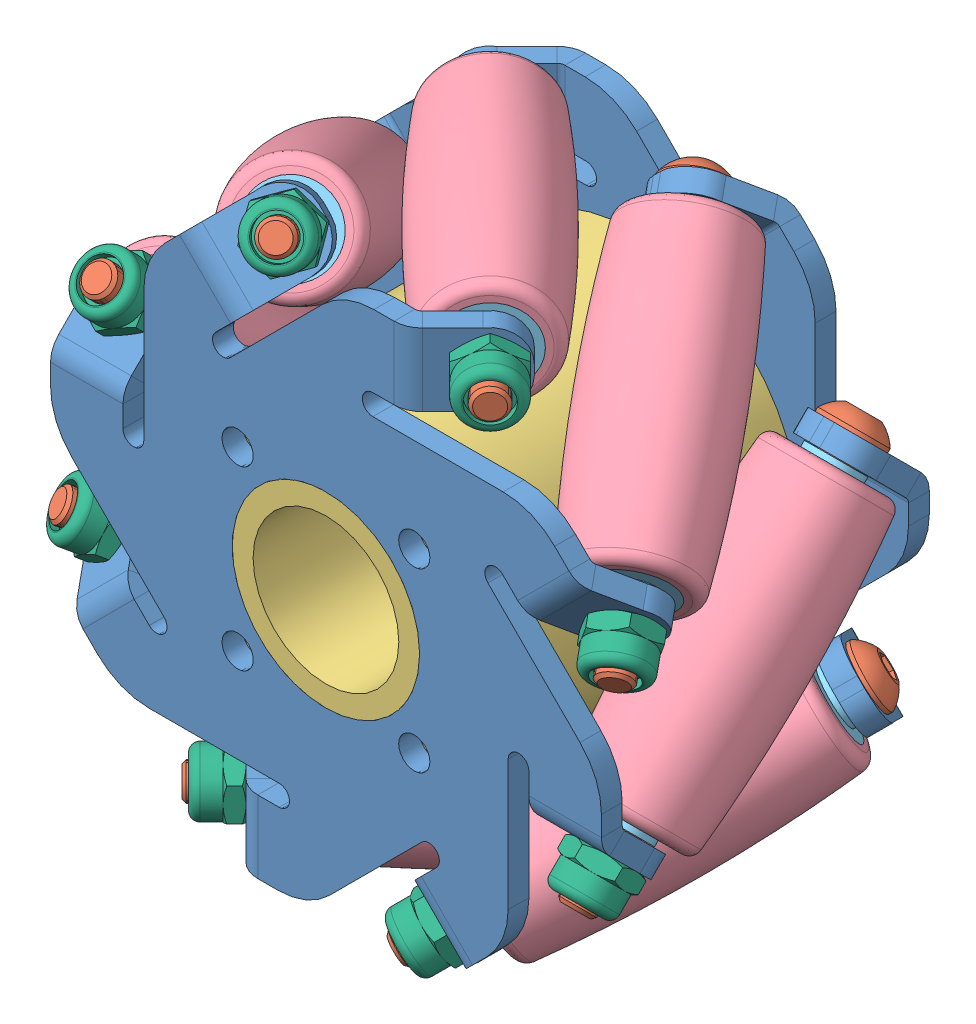
SolidWorks assembly right_mecanum_wheel, configuration Default. Lengths in mm.
Overall size (61.84 61.84 33.18).
43 component instances, 6 part files, 31 mates.
Components (placement in the parent):
- right_mecanum_frame-1: right_mecanum_frame [Default] at (32.0688 0 33.9664) size (55.02 55.02 7.58)
- boult-M3-1: boult-M3 [Default] at (39.2302 25.3656 5.3218) x (0.5 -0.5 0.707107) z (-0.707107 0.235702 0.666667) size (39.15 5.7 5.7)
- connector-1: connector [Default] at (32.0688 0 4.4664) size (32 32 31.5)
- roller-1: roller [Default] at (48.3402 16.2556 18.2053) x (0.5 -0.5 0.707107) z (-0.239472 0.704836 0.667727) size (28 12.44 12.44)
- roller_brackets-1: roller_brackets [Default] at (54.5902 10.0056 27.0441) x (0.748047 -0.162072 -0.643551) z (0.5 -0.5 0.707107) size (7.5 7.5 2)
- right_mecanum_frame-2: right_mecanum_frame [Default] at (32.0688 0 2.4664) x (-1 0 0) z (0 0 -1) size (55.02 55.02 7.58)
- roller_brackets-2: roller_brackets [Default] at (42.0902 22.5056 9.3664) x (-0.748047 0.162072 0.643551) z (-0.5 0.5 -0.707107) size (7.5 7.5 2)
- roller_brackets-3: roller_brackets [Default] at (55.0688 8.8277 9.3664) x (-0.414347 0.643551 0.643551) z (0 0.707107 -0.707107) size (7.5 7.5 2)
- roller_brackets-4: roller_brackets [Default] at (54.5744 -10.0213 9.3664) x (0.162072 0.748047 0.643551) z (0.5 0.5 -0.707107) size (7.5 7.5 2)
- roller_brackets-5: roller_brackets [Default] at (40.8965 -23 9.3664) x (0.643551 0.414347 0.643551) z (0.707107 0 -0.707107) size (7.5 7.5 2)
- roller_brackets-6: roller_brackets [Default] at (22.0475 -22.5056 9.3664) x (0.748047 -0.162072 0.643551) z (0.5 -0.5 -0.707107) size (7.5 7.5 2)
- roller_brackets-7: roller_brackets [Default] at (9.0688 -8.8277 9.3664) x (0.414347 -0.643551 0.643551) z (0 -0.707107 -0.707107) size (7.5 7.5 2)
- roller_brackets-8: roller_brackets [Default] at (9.5633 10.0213 9.3664) x (-0.162072 -0.748047 0.643551) z (-0.5 -0.5 -0.707107) size (7.5 7.5 2)
- roller_brackets-9: roller_brackets [Default] at (23.2411 23 9.3664) x (-0.643551 -0.414347 0.643551) z (-0.707107 0 -0.707107) size (7.5 7.5 2)
- roller_brackets-10: roller_brackets [Default] at (55.0688 -8.85 27.0441) x (0.414347 -0.643551 -0.643551) z (0 -0.707107 0.707107) size (7.5 7.5 2)
- roller_brackets-11: roller_brackets [Default] at (42.0744 -22.5213 27.0441) x (-0.162072 -0.748047 -0.643551) z (-0.5 -0.5 0.707107) size (7.5 7.5 2)
- roller_brackets-12: roller_brackets [Default] at (23.2188 -23 27.0441) x (-0.643551 -0.414347 -0.643551) z (-0.707107 0 0.707107) size (7.5 7.5 2)
- roller_brackets-13: roller_brackets [Default] at (9.5475 -10.0056 27.0441) x (-0.748047 0.162072 -0.643551) z (-0.5 0.5 0.707107) size (7.5 7.5 2)
- roller_brackets-14: roller_brackets [Default] at (9.0688 8.85 27.0441) x (-0.414347 0.643551 -0.643551) z (0 0.707107 0.707107) size (7.5 7.5 2)
- roller_brackets-15: roller_brackets [Default] at (22.0633 22.5213 27.0441) x (0.162072 0.748047 -0.643551) z (0.5 0.5 0.707107) size (7.5 7.5 2)
- roller_brackets-16: roller_brackets [Default] at (40.9188 23 27.0441) x (0.643551 0.414347 -0.643551) z (0.707107 0 0.707107) size (7.5 7.5 2)
- roller-2: roller [Default] at (55.0688 -0.0111 18.2053) x (0 -0.707107 0.707107) z (0.329062 0.667727 0.667727) size (28 12.44 12.44)
- roller-3: roller [Default] at (48.3244 -16.2713 18.2053) x (-0.5 -0.5 0.707107) z (0.704836 0.239472 0.667727) size (28 12.44 12.44)
- roller-4: roller [Default] at (32.0577 -23 18.2053) x (-0.707107 0 0.707107) z (0.667727 -0.329062 0.667727) size (28 12.44 12.44)
- roller-5: roller [Default] at (15.7975 -16.2556 18.2053) x (-0.5 0.5 0.707107) z (0.239472 -0.704836 0.667727) size (28 12.44 12.44)
- roller-6: roller [Default] at (9.0688 0.0111 18.2053) x (0 0.707107 0.707107) z (-0.329062 -0.667727 0.667727) size (28 12.44 12.44)
- roller-7: roller [Default] at (15.8133 16.2713 18.2053) x (0.5 0.5 0.707107) z (-0.704836 -0.239472 0.667727) size (28 12.44 12.44)
- roller-8: roller [Default] at (32.08 23 18.2053) x (0.707107 0 0.707107) z (-0.667727 0.329062 0.667727) size (28 12.44 12.44)
- boult-M3-2: boult-M3 [Default] at (55.0688 12.8723 5.3218) x (0 -0.707107 0.707107) z (-0.333333 0.666667 0.666667) size (39.15 5.7 5.7)
- boult-M3-3: boult-M3 [Default] at (57.4344 -7.1613 5.3218) x (-0.5 -0.5 0.707107) z (0.235702 0.707107 0.666667) size (39.15 5.7 5.7)
- boult-M3-4: boult-M3 [Default] at (44.9412 -23 5.3218) x (-0.707107 0 0.707107) z (0.666667 0.333333 0.666667) size (39.15 5.7 5.7)
- boult-M3-5: boult-M3 [Default] at (24.9075 -25.3656 5.3218) x (-0.5 0.5 0.707107) z (0.707107 -0.235702 0.666667) size (39.15 5.7 5.7)
- boult-M3-6: boult-M3 [Default] at (9.0688 -12.8723 5.3218) x (0 0.707107 0.707107) z (0.333333 -0.666667 0.666667) size (39.15 5.7 5.7)
- boult-M3-7: boult-M3 [Default] at (6.7032 7.1613 5.3218) x (0.5 0.5 0.707107) z (-0.235702 -0.707107 0.666667) size (39.15 5.7 5.7)
- boult-M3-8: boult-M3 [Default] at (19.1965 23 5.3218) x (0.707107 0 0.707107) z (-0.666667 -0.333333 0.666667) size (39.15 5.7 5.7)
- torque nut 08_iso-1: torque nut 08_iso [ISO 10511-M3-N] at (57.4002 7.1956 31.0181) x (-0.70952 0.231664 0.665518) z (0.5 -0.5 0.707107) size (5.5 6.35 3.9)
- torque nut 08_iso-2: torque nut 08_iso [ISO 10511-M3-N] at (44.8928 23 31.0181) x (0.707107 0 -0.707107) z (0.707107 0 0.707107) size (5.5 6.35 3.9)
- torque nut 08_iso-3: torque nut 08_iso [ISO 10511-M3-N] at (24.8733 25.3313 31.0181) x (0.853553 -0.146447 -0.5) z (0.5 0.5 0.707107) size (5.5 6.35 3.9)
- torque nut 08_iso-4: torque nut 08_iso [ISO 10511-M3-N] at (9.0688 12.8239 31.0181) x (1 0 0) z (0 0.707107 0.707107) size (5.5 6.35 3.9)
- torque nut 08_iso-5: torque nut 08_iso [ISO 10511-M3-N] at (6.7375 -7.1956 31.0181) x (0.853553 0.146447 0.5) z (-0.5 0.5 0.707107) size (5.5 6.35 3.9)
- torque nut 08_iso-6: torque nut 08_iso [ISO 10511-M3-N] at (19.2449 -23 31.0181) x (0.707107 0 0.707107) z (-0.707107 0 0.707107) size (5.5 6.35 3.9)
- torque nut 08_iso-7: torque nut 08_iso [ISO 10511-M3-N] at (39.2644 -25.3313 31.0181) x (0.853553 -0.146447 0.5) z (-0.5 -0.5 0.707107) size (5.5 6.35 3.9)
- torque nut 08_iso-8: torque nut 08_iso [ISO 10511-M3-N] at (55.0688 -12.8239 31.0181) x (1 0 0) z (0 -0.707107 0.707107) size (5.5 6.35 3.9)
Mates (geometry in assembly coordinates):
- Concentric1: concentric anti-aligned: cylinder of right_mecanum_frame-1 through (32.0688 0 31.9664) axis (0 0 1) radius 9; cylinder of connector-1 through (32.0688 0 31.9664) axis (0 0 -1) radius 7
- Coincident1: coincident anti-aligned: plane of right_mecanum_frame-1 through (36.5688 18.5 31.9664) normal (0 0 -1); plane of connector-1 through (32.0688 0 31.9664) normal (0 0 1)
- Concentric2: concentric anti-aligned: cylinder of right_mecanum_frame-1 through (23.5835 8.4853 31.9664) axis (0 0 1) radius 1.5; cylinder of connector-1 through (23.5835 8.4853 31.9664) axis (0 0 -1) radius 1.5
- Concentric3: concentric aligned: cylinder of connector-1 through (32.0688 0 31.9664) axis (0 0 -1) radius 7; cylinder of right_mecanum_frame-2 through (32.0688 0 4.4664) axis (0 0 -1) radius 9
- Coincident2: coincident anti-aligned: plane of connector-1 through (32.0688 0 4.4664) normal (0 0 -1); plane of right_mecanum_frame-2 through (27.5688 18.5 4.4664) normal (0 0 1)
- Concentric4: concentric aligned: cylinder of connector-1 through (23.5835 8.4853 31.9664) axis (0 0 -1) radius 1.5; cylinder of right_mecanum_frame-2 through (23.5835 8.4853 4.4664) axis (0 0 -1) radius 1.5
- Coincident3: coincident anti-aligned: plane of roller-1 through (55.8386 10.7604 26.6951) normal (0.5 -0.5 0.707107); plane of roller_brackets-1 through (54.5902 10.0056 27.0441) normal (-0.5 0.5 -0.707107)
- Concentric5: concentric aligned: cylinder of roller-1 through (10.8402 53.7556 -34.8277) axis (-0.5 0.5 -0.707107) radius 1.5; cylinder of roller_brackets-1 through (55.5902 9.0056 28.4583) axis (-0.5 0.5 -0.707107) radius 1.5
- Coincident4: coincident anti-aligned: plane of roller-1 through (43.3386 23.2604 9.0174) normal (-0.5 0.5 -0.707107); plane of roller_brackets-2 through (42.0902 22.5056 9.3664) normal (0.5 -0.5 0.707107)
- Concentric6: concentric anti-aligned: cylinder of roller-1 through (10.8402 53.7556 -34.8277) axis (-0.5 0.5 -0.707107) radius 1.5; cylinder of roller_brackets-2 through (41.0902 23.5056 7.9522) axis (0.5 -0.5 0.707107) radius 1.5
- Width2: width anti-aligned: plane of roller_brackets-1 through (55.3402 9.2556 28.1048) normal (0.5 -0.5 0.707107); plane of roller_brackets-2 through (41.3402 23.2556 8.3058) normal (-0.5 0.5 -0.707107); plane of right_mecanum_frame-1 through (39.662 15.4069 44.3467) normal (-0.5 0.5 -0.707107); plane of right_mecanum_frame-2 through (29.8942 16.1746 10.5862) normal (0.5 -0.5 0.707107)
- Concentric7: concentric anti-aligned: cylinder of right_mecanum_frame-1 through (55.6252 8.9706 28.5078) axis (0.5 -0.5 0.707107) radius 1.5; cylinder of roller-1 through (10.8402 53.7556 -34.8277) axis (-0.5 0.5 -0.707107) radius 1.5
- Concentric8: concentric aligned: cylinder of boult-M3-1 through (39.2302 25.3656 5.3218) axis (-0.5 0.5 -0.707107) radius 1.5; cylinder of roller-1 through (10.8402 53.7556 -34.8277) axis (-0.5 0.5 -0.707107) radius 1.5
- Coincident6: coincident anti-aligned: plane of boult-M3-1 through (40.8052 25.7906 6.8421) normal (0.5 -0.5 0.707107); plane of right_mecanum_frame-2 through (28.8942 17.1746 9.172) normal (-0.5 0.5 -0.707107)
- Concentric10: concentric aligned: cylinder of right_mecanum_frame-1 through (42.3825 23 28.5078) axis (0.707107 0 0.707107) radius 1.5; cylinder of torque nut 08_iso-2 through (58.3631 23 44.4884) axis (0.707107 0 0.707107) radius 1.5
- Coincident7: coincident anti-aligned: plane of right_mecanum_frame-1 through (38.1399 18.5 35.5789) normal (0.707107 0 0.707107); plane of torque nut 08_iso-2 through (43.7967 26.1754 29.922) normal (-0.707107 0 -0.707107)
- Concentric11: concentric aligned: cylinder of right_mecanum_frame-1 through (23.0983 23.5563 28.5078) axis (0.5 0.5 0.707107) radius 1.5; cylinder of torque nut 08_iso-3 through (34.3983 34.8563 44.4884) axis (0.5 0.5 0.707107) radius 1.5
- Coincident8: coincident anti-aligned: plane of right_mecanum_frame-1 through (35.2434 17.1746 27.2609) normal (0.5 0.5 0.707107); plane of torque nut 08_iso-3 through (23.6332 27.2667 28.3343) normal (-0.5 -0.5 -0.707107)
- Concentric12: concentric aligned: cylinder of right_mecanum_frame-1 through (9.0688 10.3137 28.5078) axis (0 0.707107 0.707107) radius 1.5; cylinder of torque nut 08_iso-4 through (9.0688 26.2943 44.4884) axis (0 0.707107 0.707107) radius 1.5
- Coincident9: coincident anti-aligned: plane of right_mecanum_frame-1 through (36.5688 15.9706 25.6794) normal (0 0.707107 0.707107); plane of torque nut 08_iso-4 through (9.0688 13.9733 27.6767) normal (0 -0.707107 -0.707107)
- Concentric13: concentric aligned: cylinder of right_mecanum_frame-1 through (8.5125 -8.9706 28.5078) axis (-0.5 0.5 0.707107) radius 1.5; cylinder of torque nut 08_iso-5 through (-2.7875 2.3294 44.4884) axis (-0.5 0.5 0.707107) radius 1.5
- Coincident10: coincident anti-aligned: plane of right_mecanum_frame-1 through (36.5762 18.4926 31.7609) normal (-0.5 0.5 0.707107); plane of torque nut 08_iso-5 through (7.9775 -5.2602 28.3343) normal (0.5 -0.5 -0.707107)
- Concentric14: concentric aligned: cylinder of right_mecanum_frame-1 through (21.7551 -23 28.5078) axis (-0.707107 0 0.707107) radius 1.5; cylinder of torque nut 08_iso-6 through (5.7745 -23 44.4884) axis (-0.707107 0 0.707107) radius 1.5
- Coincident11: coincident anti-aligned: plane of right_mecanum_frame-1 through (32.3617 18.5 41.9429) normal (-0.707107 0 0.707107); plane of torque nut 08_iso-6 through (20.3409 -19.8246 29.922) normal (0.707107 0 -0.707107)
- Concentric15: concentric aligned: cylinder of right_mecanum_frame-1 through (41.0394 -23.5563 28.5078) axis (-0.5 -0.5 0.707107) radius 1.5; cylinder of torque nut 08_iso-7 through (29.7394 -34.8563 44.4884) axis (-0.5 -0.5 0.707107) radius 1.5
- Coincident12: coincident anti-aligned: plane of right_mecanum_frame-1 through (31.1577 13.0888 50.2609) normal (-0.5 -0.5 0.707107); plane of torque nut 08_iso-7 through (39.5744 -21.8459 31.5098) normal (0.5 0.5 -0.707107)
- Concentric16: concentric aligned: cylinder of right_mecanum_frame-1 through (55.0688 -10.3137 28.5078) axis (0 -0.707107 0.707107) radius 1.5; cylinder of torque nut 08_iso-8 through (55.0688 -26.2943 44.4884) axis (0 -0.707107 0.707107) radius 1.5
- Coincident13: coincident anti-aligned: plane of right_mecanum_frame-1 through (36.5688 10.1924 51.8424) normal (0 -0.707107 0.707107); plane of torque nut 08_iso-8 through (55.0688 -9.4825 32.1674) normal (0 0.707107 -0.707107)
- Concentric17: concentric anti-aligned: cylinder of boult-M3-1 through (39.2302 25.3656 5.3218) axis (-0.5 0.5 -0.707107) radius 1.5; cylinder of torque nut 08_iso-1 through (56.6252 7.9706 29.922) axis (0.5 -0.5 0.707107) radius 1.25
- Coincident15: coincident anti-aligned: plane of right_mecanum_frame-1 through (40.662 14.4069 45.7609) normal (0.5 -0.5 0.707107); plane of torque nut 08_iso-1 through (55.0484 5.3208 29.1633) normal (-0.5 0.5 -0.707107)
- Coincident16: coincident aligned: plane of connector-1 through (32.0688 0 4.4664) normal (0 1 0)
